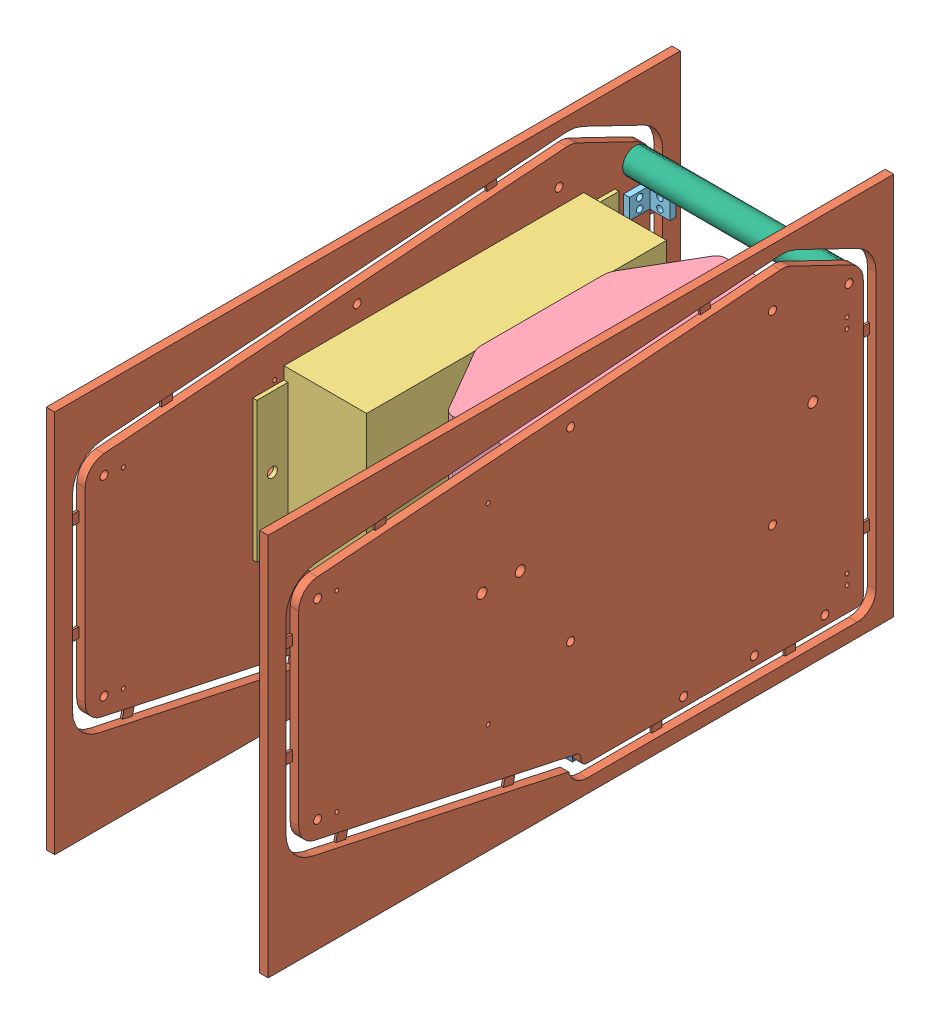
SolidWorks assembly Assem1, configuration Default. Lengths in mm.
Overall size (110 190 310).
11 component instances, 7 part files, 16 mates.
Components (placement in the parent):
- top_plate-1: top_plate [Predeterminado] at (41.3277 71.3859 101.6026) x (-1 0 0) z (0 -1 0) size (101.6 140 9.53)
- Derecho_m-2: Derecho_m [Default] at (-9.4723 61.8634 47.6026) x (0 0 1) z (-1 0 0) size (310 190 4.2)
- driver-1: driver [Default] at (-9.4723 201.8152 228.9026) x (0 0 -1) z (1 0 0) size (179.4 81.8 41)
- Derecho_m-3: Derecho_m [Default] at (96.3277 61.8634 47.6026) x (0 0 1) z (-1 0 0) size (310 190 4.2)
- batería-1: batería [Default] at (35.1277 206.2188 213.2089) x (0 0 -1) z (1 0 0) size (135.6 83.6 57)
- acrilico-1: acrilico [Default] at (-13.6723 206.8609 44.6026) size (109.6 145 3) (hidden)
- Angulo-1: Angulo [Default] at (-9.4723 81.3884 60.6026) x (0 0 -1) z (1 0 0) size (13 10 13)
- Angulo-2: Angulo [Default] at (79.1277 81.3884 47.6026) size (13 10 13)
- Angulo-3: Angulo [Default] at (79.1277 191.3884 47.6026) size (13 10 13)
- Angulo-4: Angulo [Default] at (-9.4723 191.3884 60.6026) x (0 0 -1) z (1 0 0) size (13 10 13)
- varilla-1: varilla [Default] at (-9.4723 202.8698 54.701) x (0 0 -1) z (1 0 0) size (12.7 12.7 101.6)
Mates (geometry in assembly coordinates):
- Concentric1: concentric aligned: circle of top_plate-1; circle of Derecho_m-2
- Concentric2: concentric aligned: circle of top_plate-1; circle of Derecho_m-2
- Coincident1: coincident anti-aligned: plane of top_plate-1 through (-9.4723 61.8609 47.6026) normal (-1 0 0); plane of Derecho_m-2 through (-9.4723 61.8634 47.6026) normal (1 0 0)
- Coincident2: coincident: circle of Derecho_m-2; circle of driver-1
- Coincident3: coincident aligned: cylinder of Derecho_m-2; cylinder of driver-1 through (-7.4723 160.9152 236.6026) axis (-1 0 0) radius 2.5
- Concentric3: concentric anti-aligned: circle of top_plate-1; circle of Derecho_m-3
- Concentric4: concentric anti-aligned: circle of top_plate-1; circle of Derecho_m-3
- Coincident4: coincident anti-aligned: plane of top_plate-1 through (92.1277 61.8609 47.6026) normal (1 0 0); plane of Derecho_m-3 through (92.1277 61.8634 47.6026) normal (-1 0 0)
- Coincident5: coincident anti-aligned: plane of Derecho_m-3 through (92.1277 61.8634 47.6026) normal (-1 0 0); plane of batería-1 through (92.1277 206.2188 213.2089) normal (1 0 0)
- Coincident6: coincident aligned: line of top_plate-1 through (-9.4723 61.8609 47.6026) axis (1 0 0); line of acrilico-1 through (-13.6723 61.8609 47.6026) axis (1 0 0)
- Coincident8: coincident aligned: line of Derecho_m-2 through (-13.6723 201.1425 47.6026) axis (0 -1 0); line of acrilico-1 through (-13.6723 206.8609 47.6026) axis (0 -1 0)
- Coincident9: coincident: circle of Derecho_m-2; circle of Angulo-1
- Coincident11: coincident: circle of Derecho_m-3; circle of Angulo-2
- Coincident12: coincident: circle of Derecho_m-3; circle of Angulo-3
- Coincident13: coincident: circle of Derecho_m-2; circle of Angulo-4
- Coincident14: coincident anti-aligned: circle of Derecho_m-3; circle of varilla-1
